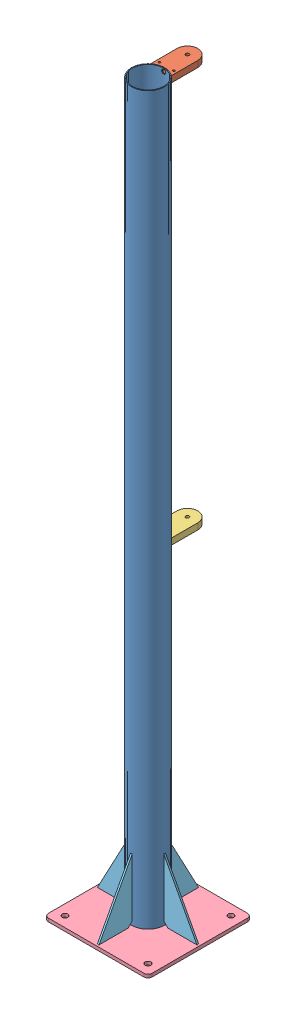
SolidWorks assembly Ftx_Support, configuration Défaut. Lengths in mm.
Overall size (250 1758 250).
8 component instances, 5 part files, 25 mates.
Components (placement in the parent):
- Tube_80x2x1750-1: Tube_80x2x1750 [Défaut] at (-29.6678 -485.0572 0) size (80 1750 80)
- Ftx_BrideStatorSup-1: Ftx_BrideStatorSup [Défaut] at (-29.6678 1264.9428 0) x (-1 0 0) z (0 0 1) size (50 15 88.78)
- Ftx_BrideStatorInf-1: Ftx_BrideStatorInf [Défaut] at (-29.6678 284.9428 0) size (50 15 88.78)
- Ftx_Platine-1: Ftx_Platine [Défaut] at (-154.6678 -493.0572 125) size (250 8 250)
- Ftx_Renfort-2: Ftx_Renfort [Défaut] at (-149.6678 -485.0572 0) size (80 150 4)
- Ftx_Renfort-3: Ftx_Renfort [Défaut] at (-29.6678 -485.0572 120) x (0 0 -1) z (1 0 0) size (80 150 4)
- Ftx_Renfort-4: Ftx_Renfort [Défaut] at (90.3322 -485.0572 0) x (-1 0 0) z (0 0 -1) size (80 150 4)
- Ftx_Renfort-5: Ftx_Renfort [Défaut] at (-29.6678 -485.0572 -120) x (0 0 1) z (-1 0 0) size (80 150 4)
Mates (geometry in assembly coordinates):
- Distance1: distance = 0 mm aligned: plane of Tube_80x2x1750-1 through (-29.6678 1264.9428 0) normal (0 1 0); plane of Ftx_BrideStatorSup-1 through (-29.6678 1264.9428 0) normal (0 1 0)
- Coaxiale1: concentric anti-aligned: cylinder of Tube_80x2x1750-1 through (-29.6678 1264.9428 0) axis (0 -1 0) radius 40; cylinder of Ftx_BrideStatorSup-1 through (-29.6678 1249.9428 0) axis (0 1 0) radius 40
- Coaxiale4: concentric aligned: cylinder of Tube_80x2x1750-1 through (-29.6678 1264.9428 0) axis (0 -1 0) radius 40; cylinder of Ftx_BrideStatorInf-1 through (-29.6678 299.9428 0) axis (0 -1 0) radius 40
- Coaxiale5: concentric anti-aligned: cylinder of Ftx_BrideStatorSup-1 through (-29.6678 1249.9428 -95) axis (0 1 0) radius 25; cylinder of Ftx_BrideStatorInf-1 through (-29.6678 299.9428 -95) axis (0 -1 0) radius 25
- Distance3: distance = 950 mm anti-aligned: plane of Ftx_BrideStatorSup-1 through (-29.6678 1249.9428 0) normal (0 -1 0); plane of Ftx_BrideStatorInf-1 through (-29.6678 299.9428 0) normal (0 1 0)
- Perpendiculaire2: perpendicular: line of Tube_80x2x1750-1 through (10.3322 1264.9428 0) axis (-1 0 0); cylinder of Ftx_BrideStatorSup-1 through (-29.6678 1257.4428 -120.001) axis (0 0 1) radius 4.15
- Coïncidente1: coincident anti-aligned: plane of Tube_80x2x1750-1 through (-29.6678 -485.0572 0) normal (0 -1 0); plane of Ftx_Platine-1 through (-144.6678 -485.0572 115) normal (0 1 0)
- Coïncidente6: coincident aligned: line of Tube_80x2x1750-1 through (10.3322 -485.0572 0) axis (-1 0 0); line of Ftx_Platine-1 through (95.3322 -485.0572 0) axis (-1 0 0)
- Coïncidente7: coincident aligned: line of Tube_80x2x1750-1 through (-29.6678 -485.0572 -40) axis (0 0 1); line of Ftx_Platine-1 through (-29.6678 -485.0572 -125) axis (0 0 1)
- Coïncidente8: coincident anti-aligned: plane of Ftx_Platine-1 through (-144.6678 -485.0572 115) normal (0 1 0); plane of Ftx_Renfort-2 through (-149.6678 -485.0572 2) normal (0 -1 0)
- Coïncidente9: coincident: line of Ftx_Platine-1 through (95.3322 -485.0572 0) axis (-1 0 0); moEndPointRef_w of Ftx_Renfort-2
- Parallèle2: parallel aligned: plane of Ftx_Platine-1 through (-144.6678 -485.0572 125) normal (0 0 1); plane of Ftx_Renfort-2 through (-149.6678 -485.0572 2) normal (0 0 1)
- Tangent2: tangent anti-aligned: cylinder of Tube_80x2x1750-1 through (-29.6678 1264.9428 0) axis (0 -1 0) radius 40; plane of Ftx_Renfort-2 through (-69.6678 -475.0572 2) normal (1 0 0)
- Coïncidente10: coincident anti-aligned: plane of Ftx_Platine-1 through (-144.6678 -485.0572 115) normal (0 1 0); plane of Ftx_Renfort-3 through (-27.6678 -485.0572 120) normal (0 -1 0)
- Coïncidente11: coincident: line of Ftx_Platine-1 through (-29.6678 -485.0572 -125) axis (0 0 1); moEndPointRef_w of Ftx_Renfort-3
- Parallèle3: parallel aligned: plane of Ftx_Platine-1 through (95.3322 -485.0572 115) normal (1 0 0); plane of Ftx_Renfort-3 through (-27.6678 -485.0572 120) normal (1 0 0)
- Tangent3: tangent anti-aligned: cylinder of Tube_80x2x1750-1 through (-29.6678 1264.9428 0) axis (0 -1 0) radius 40; plane of Ftx_Renfort-3 through (-27.6678 -475.0572 40) normal (0 0 -1)
- Coïncidente12: coincident anti-aligned: plane of Ftx_Platine-1 through (-144.6678 -485.0572 115) normal (0 1 0); plane of Ftx_Renfort-4 through (90.3322 -485.0572 -2) normal (0 -1 0)
- Coïncidente13: coincident: line of Ftx_Platine-1 through (95.3322 -485.0572 0) axis (-1 0 0); moEndPointRef_w of Ftx_Renfort-4
- Parallèle4: parallel anti-aligned: plane of Ftx_Platine-1 through (-144.6678 -485.0572 125) normal (0 0 1); plane of Ftx_Renfort-4 through (90.3322 -485.0572 -2) normal (0 0 -1)
- Tangent4: tangent anti-aligned: cylinder of Tube_80x2x1750-1 through (-29.6678 1264.9428 0) axis (0 -1 0) radius 40; plane of Ftx_Renfort-4 through (10.3322 -475.0572 -2) normal (-1 0 0)
- Coïncidente14: coincident anti-aligned: plane of Ftx_Platine-1 through (-144.6678 -485.0572 115) normal (0 1 0); plane of Ftx_Renfort-5 through (-31.6678 -485.0572 -120) normal (0 -1 0)
- Coïncidente15: coincident: line of Ftx_Platine-1 through (-29.6678 -485.0572 -125) axis (0 0 1); moEndPointRef_w of Ftx_Renfort-5
- Parallèle5: parallel anti-aligned: plane of Ftx_Platine-1 through (95.3322 -485.0572 115) normal (1 0 0); plane of Ftx_Renfort-5 through (-31.6678 -485.0572 -120) normal (-1 0 0)
- Tangent5: tangent anti-aligned: cylinder of Tube_80x2x1750-1 through (-29.6678 1264.9428 0) axis (0 -1 0) radius 40; plane of Ftx_Renfort-5 through (-31.6678 -475.0572 -40) normal (0 0 1)
